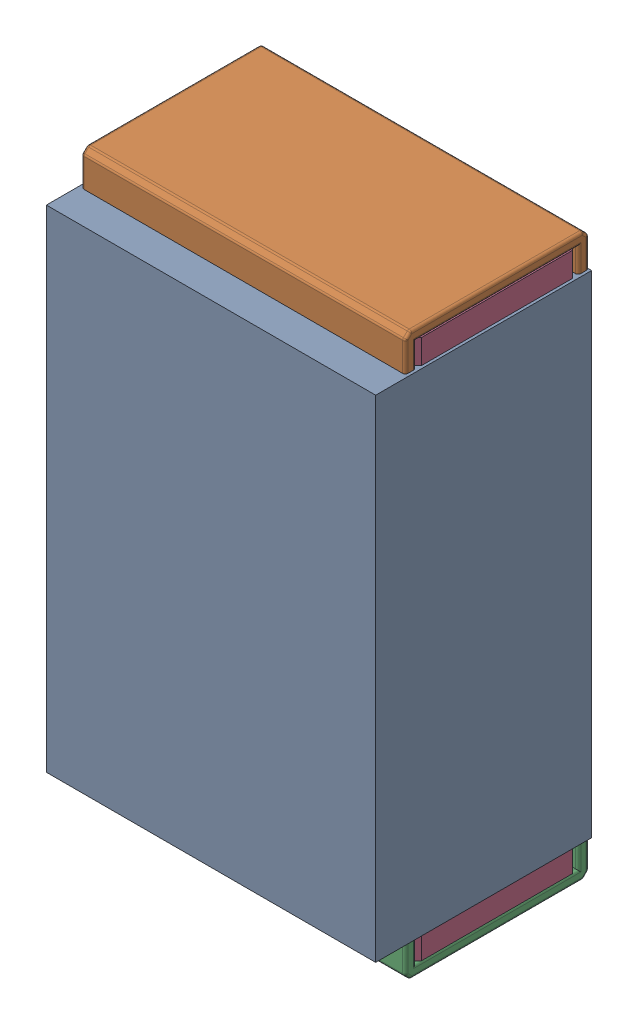
SolidWorks assembly R13, configuration Default. Lengths in mm.
Overall size (0.61 1.04 0.4).
3 component instances, 2 part files, 0 mates.
Components (placement in the parent):
- 1088881848-1: 1088881848 [Default] at (6.225 20.875 0) size (0.61 0.91 0.4)
  - Extruded-1-1: Extruded-1 [Default] at origin size (0.61 0.91 0.4)
- R0402-1: R0402 [Default] at (6.225 20.875 0) x (0 1 0) z (1 0 0) size (1.04 0.34 0.6)
